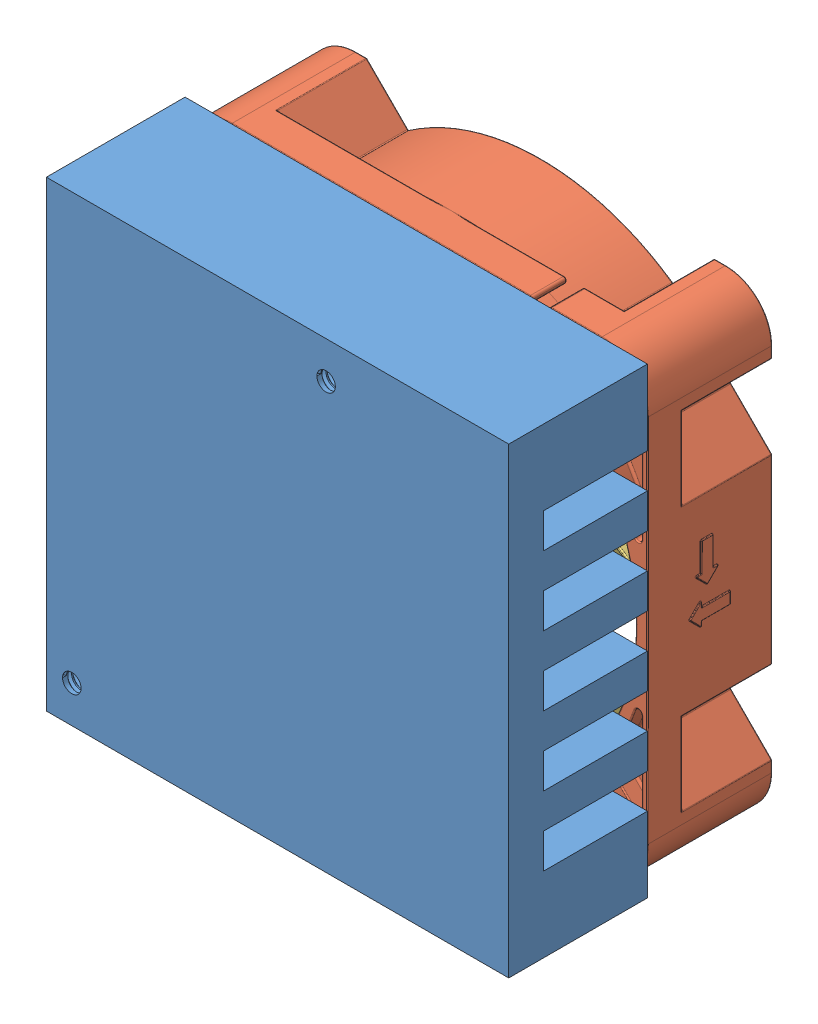
SolidWorks assembly Tiny Heatsink with Fan, configuration Default. Lengths in mm.
Overall size (40.11 40.01 22.86).
4 component instances, 3 part files, 3 mates.
Components (placement in the parent):
- Tiny Heatsink-1: Tiny Heatsink [Default] at (191.4867 -14.133 198.9648) size (40 40 12.05)
- CPU - -KF0410-01-1: CPU - -KF0410-01 [По умолчанию] at (205.1477 178.1124 195.9648) x (0 -1 0) z (0 0 -1) size (40.01 40.11 10.82)
  - CPU - -KF0410-01-PLASTIC CASING-1: CPU - -KF0410-01-PLASTIC CASING [По умолчанию] at (0.9289 7.0036 0) size (40.01 40.11 10.81)
  - CPU - -KF0410-01- PLASTIC ROTOR-1: CPU - -KF0410-01- PLASTIC ROTOR [По умолчанию] at (0.9289 7.0036 -1) size (37.4 37 9.12)
Mates (geometry in assembly coordinates):
- Coincident1: coincident anti-aligned: plane of Tiny Heatsink-1 through (191.4867 -14.133 198.9648) normal (0 0 -1); plane of CPU - -KF0410-01-1/CPU - -KF0410-01-PLASTIC CASING-1 through (217.0887 188.6321 198.9648) normal (0 0 1)
- Concentric1: concentric aligned: circle of Tiny Heatsink-1; cylinder of CPU - -KF0410-01-1/CPU - -KF0410-01-PLASTIC CASING-1 through (182.1441 193.1834 191.0648) axis (0 0 1) radius 1.5
- Concentric2: concentric aligned: circle of Tiny Heatsink-1; cylinder of CPU - -KF0410-01-1/CPU - -KF0410-01-PLASTIC CASING-1 through (214.1441 161.1834 191.0648) axis (0 0 1) radius 1.5
